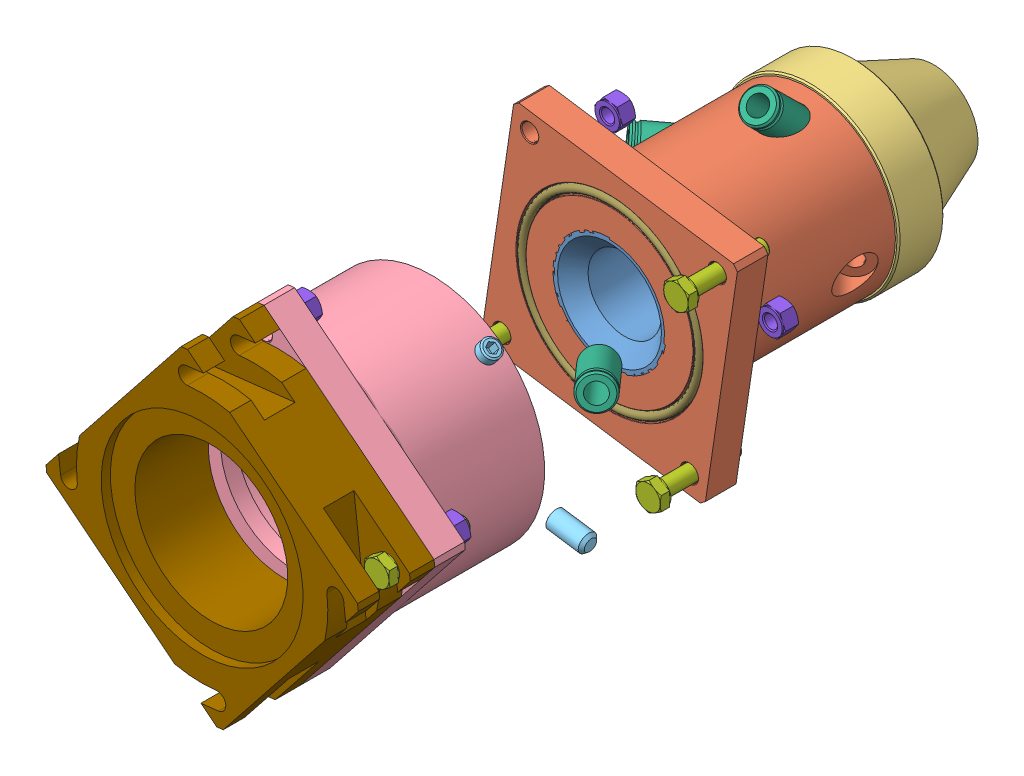
SolidWorks assembly 0Montagem _BOM, configuration Valor predeterminado. Lengths in mm.
Overall size (109.44 103.97 239.19).
36 component instances, 14 part files, 67 mates.
Components (placement in the parent):
- 1Câmara de mistura-1: 1Câmara de mistura [Valor predeterminado] at (-3.7067 1.39 80) size (39.8 39.8 80)
- 2Invólucro-1: 2Invólucro [Valor predeterminado] at (-3.7067 1.39 79.5) x (-0.989121 0.147103 0) z (0 0 1) size (74 74 80)
- 3bocal_interno-1: 3bocal_interno [Valor predeterminado] at (-3.7067 1.39 -19.2681) x (0.242577 -0.970132 0) z (-0.970132 -0.242577 0) size (37.18 39 37.18) (hidden)
- 4bocal_externo-1: 4bocal_externo [Valor predeterminado] at (-3.7067 1.39 -20.5) x (0.998618 -0.052557 0) z (-0.052557 -0.998618 0) size (59 41 59)
- Separador Inferior-1: Separador Inferior [Valor predeterminado] at (-3.7067 1.39 79.5) x (0.147103 0.989121 0) z (0 0 1) size (74 74 91.5) (hidden)
- Separador Superior-1: Separador Superior [Valor predeterminado] at (-3.7067 1.39 177.6934) x (-0.783053 0.621956 0) z (0 0 1) size (74 74 50)
- socket set screw flat point_iso-8: socket set screw flat point_iso [ISO 4026 - M6 x 12-N] at (21.1716 32.7121 142.6934) x (-0.621956 -0.783053 0) z (-0.41719 0.331362 0.846257) size (12 6 6)
- socket set screw flat point_iso-10: socket set screw flat point_iso [ISO 4026 - M6 x 12-N] at (-7.5043 11.0106 142.6934) x (-0.367166 0.930156 0) z (0.914857 0.361127 -0.180621) size (12 6 6) (hidden)
- socket set screw flat point_iso-15: socket set screw flat point_iso [ISO 4026 - M6 x 12-N] at (41.4083 -5.3195 142.6934) x (0.989121 -0.147103 0) z (-0.009687 -0.065137 -0.997829) size (12 6 6)
- conector_reto_aventics_1823373040-1: conector_reto_aventics_1823373040 [Valor predeterminado] at (-7.3078 -22.8243 23.4105) x (0.664276 -0.577991 -0.473986) z (0.104018 0.699414 -0.707107) size (10.5 10.5 22.5) (hidden)
- conector_reto_aventics_1823373040-2: conector_reto_aventics_1823373040 [Valor predeterminado] at (-7.9051 -26.8402 109.3995) x (0.664276 -0.577991 -0.473986) z (0.104018 0.699414 -0.707107) size (10.5 10.5 22.5)
- conector_reto_aventics_1823373040-3: conector_reto_aventics_1823373040 [Valor predeterminado] at (-27.9209 4.9912 23.4105) x (0.588702 -0.477165 0.65249) z (0.699414 -0.104018 -0.707107) size (10.5 10.5 22.5)
- conector_reto_aventics_1823373040-4: conector_reto_aventics_1823373040 [Valor predeterminado] at (-26.0555 19.141 109.3995) x (0.396766 -0.607235 0.688362) z (0.553702 -0.439789 -0.707107) size (10.5 10.5 22.5) (hidden)
- conector_reto_aventics_1823373040-5: conector_reto_aventics_1823373040 [Valor predeterminado] at (22.8406 11.8691 109.3995) x (0.551622 -0.805255 -0.217432) z (-0.657719 -0.259625 -0.707107) size (10.5 10.5 22.5)
- conector_reto_aventics_1823373040-6: conector_reto_aventics_1823373040 [Valor predeterminado] at (-0.1055 25.6043 23.4105) x (0.13653 -0.714274 0.68642) z (-0.104018 -0.699414 -0.707107) size (10.5 10.5 22.5)
- conector_reto_aventics_1823373040-8: conector_reto_aventics_1823373040 [Valor predeterminado] at (20.5076 -2.2112 23.4105) x (0.420411 -0.740215 -0.524725) z (-0.699414 0.104018 -0.707107) size (10.5 10.5 22.5) (hidden)
- hex screw gradeab_iso-1: hex screw gradeab_iso [ISO 4017 - M5 x 25-N] at (-38.9296 -24.7126 93) x (0 0 -1) z (1 0 0) size (28.5 9.24 8)
- hex screw gradeab_iso-3: hex screw gradeab_iso [ISO 4017 - M5 x 25-N] at (-29.8092 36.6129 93) x (0 0 -1) z (1 0 0) size (28.5 9.24 8) (hidden)
- hex screw gradeab_iso-4: hex screw gradeab_iso [ISO 4017 - M5 x 25-N] at (31.5163 27.4926 93) x (0 0 -1) z (1 0 0) size (28.5 9.24 8)
- hex screw gradeab_iso-5: hex screw gradeab_iso [ISO 4017 - M5 x 25-N] at (22.3959 -33.833 93) x (0 0 -1) z (1 0 0) size (28.5 9.24 8)
- hex nut style 2 gradeab_iso-1: hex nut style 2 gradeab_iso [ISO - 4033 - M5 - W - N] at (-14.484 43.8853 64.4) x (0.923728 0.383049 0) z (0 0 -1) size (8 9.24 5.1)
- hex nut style 2 gradeab_iso-2: hex nut style 2 gradeab_iso [ISO - 4033 - M5 - W - N] at (-46.2019 -9.3873 64.4) x (0.923728 0.383049 0) z (0 0 -1) size (8 9.24 5.1)
- hex nut style 2 gradeab_iso-3: hex nut style 2 gradeab_iso [ISO - 4033 - M5 - W - N] at (38.7886 12.1673 64.4) x (0.923728 0.383049 0) z (0 0 -1) size (8 9.24 5.1)
- hex nut style 2 gradeab_iso-4: hex nut style 2 gradeab_iso [ISO - 4033 - M5 - W - N] at (7.0707 -41.1053 63.4) x (0.923728 0.383049 0) z (0 0 -1) size (8 9.24 5.1)
- hex nut style 2 gradeab_iso-5: hex nut style 2 gradeab_iso [ISO - 4033 - M5 - W - N] at (1.2873 -42.1653 172.5934) x (0.877581 0.479428 0) z (0 0 -1) size (8 9.24 5.1) (hidden)
- hex nut style 2 gradeab_iso-6: hex nut style 2 gradeab_iso [ISO - 4033 - M5 - W - N] at (39.8486 6.384 172.5934) x (0.923728 0.383049 0) z (0 0 -1) size (8 9.24 5.1)
- hex nut style 2 gradeab_iso-7: hex nut style 2 gradeab_iso [ISO - 4033 - M5 - W - N] at (-8.7007 44.9452 172.5934) x (0.894482 0.447104 0) z (0 0 -1) size (8 9.24 5.1)
- hex nut style 2 gradeab_iso-8: hex nut style 2 gradeab_iso [ISO - 4033 - M5 - W - N] at (-47.2619 -3.604 172.5934) x (0.923728 0.383049 0) z (0 0 -1) size (8 9.24 5.1)
- acoplamento_espaçador_precitec (1)-3: acoplamento_espaçador_precitec (1) [Valor predeterminado] at (-55.692 -4.5706 187.6934) x (0 0 1) z (-0.783053 0.621956 0) size (27 74 74)
- hex screw gradeab_iso-6: hex screw gradeab_iso [ISO 4017 - M5 x 25-N] at (-8.7007 44.9452 199.1934) x (0 0 -1) z (-0.865163 0.501491 0) size (28.5 9.24 8) (hidden)
- hex screw gradeab_iso-8: hex screw gradeab_iso [ISO 4017 - M5 x 25-N] at (1.2873 -42.1653 199.1934) x (0 0 -1) z (1 0 0) size (28.5 9.24 8) (hidden)
- hex screw gradeab_iso-9: hex screw gradeab_iso [ISO 4017 - M5 x 25-N] at (-47.2619 -3.604 199.1934) x (0 0 -1) z (0.936859 0.349707 0) size (28.5 9.24 8)
- hex screw gradeab_iso-10: hex screw gradeab_iso [ISO 4017 - M5 x 25-N] at (39.8486 6.384 199.1934) x (0 0 -1) z (0.997971 0.063675 0) size (28.5 9.24 8)
- Parker Mod. 2-143 - Material Etileno Propileno(EPDM)-Vedação Estática Cilíndrica-1: Parker Mod. 2-143 - Material Etileno Propileno(EPDM)-Vedação Estática Cilíndrica [Valor predeterminado] at (-3.7067 1.39 165.51) x (0.999508 0.031367 0) z (0 0 1) size (66.84 66.84 2.62)
- Parker Mod. 2-038 - Material Etileno Propileno(EPDM)-Vedação de Face-1: Parker Mod. 2-038 - Material Etileno Propileno(EPDM)-Vedação de Face [Valor predeterminado] at (-3.7067 1.39 188.3034) x (-0.157479 -0.987522 0) z (0 0 1) size (69.96 69.96 1.78)
- Parker Mod. 2-139 - Material Etileno Propileno(EPDM)-Vedação de Face-1: Parker Mod. 2-139 - Material Etileno Propileno(EPDM)-Vedação de Face [Valor predeterminado] at (-3.7067 1.39 78.81) x (0.912781 0.408449 0) z (0 0 1) size (60.49 60.49 2.62)
Mates (geometry in assembly coordinates):
- Concêntrico1: concentric: circle of 1Câmara de mistura-1; circle of 2Invólucro-1
- Coincidente1: coincident: plane of 1Câmara de mistura-1 through (-3.7067 13.39 79.5) normal (0 0 1); plane of 2Invólucro-1 through (-6.6487 -18.3924 79.5) normal (0 0 1)
- Concêntrico2: concentric: circle of 1Câmara de mistura-1; circle of 3bocal_interno-1
- Coincidente2: coincident: plane of 1Câmara de mistura-1 through (-3.7067 12.39 -0.5) normal (0 0 -1); plane of 3bocal_interno-1 through (-3.7067 1.39 -0.5) normal (0 0 1)
- Concêntrico3: concentric: circle of 3bocal_interno-1; circle of 4bocal_externo-1
- Coincidente3: coincident: plane of 2Invólucro-1 through (-6.7958 -19.3815 14.5) normal (0 0 -1); plane of 4bocal_externo-1 through (-2.1562 30.8492 14.5) normal (0 0 1)
- Concêntrico4: concentric: circle of 3bocal_interno-1; circle of Separador Inferior-1
- Coincidente4: coincident: plane of 2Invólucro-1 through (-6.6487 -18.3924 79.5) normal (0 0 1); plane of Separador Inferior-1 through (-3.7067 1.39 79.5) normal (0 0 -1)
- Concêntrico6: concentric: cylinder of 2Invólucro-1 through (-29.8092 36.6129 79.5) axis (0 0 1) radius 2.75; circle of Separador Inferior-1
- Concêntrico121: concentric: cylinder of Separador Superior-1 through (19.3057 30.3629 142.6934) axis (0.621956 0.783053 0) radius 2.5; cylinder of socket set screw flat point_iso-8 through (29.0704 42.6569 142.6934) axis (0.621956 0.783053 0) radius 3
- Concêntrico14: concentric: cylinder of Separador Superior-1 through (9.8785 -33.0258 142.6934) axis (0.367166 -0.930156 0) radius 2.5; cylinder of socket set screw flat point_iso-10 through (-2.8413 -0.8023 142.6934) axis (0.367166 -0.930156 0) radius 3
- Concêntrico16: concentric: cylinder of Separador Superior-1 through (-40.3041 6.8328 142.6934) axis (-0.989121 0.147103 0) radius 2.5; cylinder of socket set screw flat point_iso-15 through (28.8465 -3.4513 142.6934) axis (-0.989121 0.147103 0) radius 3
- Concêntrico17: concentric: circle of 2Invólucro-1; circle of conector_reto_aventics_1823373040-1
- Coincidente12: coincident: plane of 2Invólucro-1 through (-7.0478 -21.0757 25.1782) normal (-0.104018 -0.699414 0.707107); plane of conector_reto_aventics_1823373040-1 through (-6.8932 -17.373 28.8634) normal (0.104018 0.699414 -0.707107)
- Concêntrico18: concentric: circle of Separador Inferior-1; circle of conector_reto_aventics_1823373040-2
- Coincidente13: coincident: plane of Separador Inferior-1 through (-7.645 -25.0916 111.1673) normal (-0.104018 -0.699414 0.707107); plane of conector_reto_aventics_1823373040-2 through (-7.4905 -21.3889 114.8525) normal (0.104018 0.699414 -0.707107)
- Concêntrico19: concentric: circle of 2Invólucro-1; circle of conector_reto_aventics_1823373040-3
- Coincidente14: coincident: plane of 2Invólucro-1 through (-26.1724 4.7311 25.1782) normal (-0.699414 0.104018 0.707107); plane of conector_reto_aventics_1823373040-3 through (-28.9224 12.3611 21.3357) normal (0.699414 -0.104018 -0.707107)
- Concêntrico20: concentric: circle of Separador Inferior-1; circle of conector_reto_aventics_1823373040-4
- Coincidente15: coincident: plane of Separador Inferior-1 through (-24.6712 18.0415 111.1673) normal (-0.553702 0.439789 0.707107); plane of conector_reto_aventics_1823373040-4 through (-24.2245 26.0694 106.5241) normal (0.553702 -0.439789 -0.707107)
- Concêntrico21: concentric: circle of Separador Inferior-1; circle of conector_reto_aventics_1823373040-5
- Coincidente16: coincident: plane of Separador Inferior-1 through (21.1963 11.2201 111.1673) normal (0.657719 0.259625 0.707107); plane of conector_reto_aventics_1823373040-5 through (22.6295 19.1764 106.9129) normal (-0.657719 -0.259625 -0.707107)
- Concêntrico22: concentric: circle of 2Invólucro-1; circle of conector_reto_aventics_1823373040-6
- Coincidente17: coincident: plane of 2Invólucro-1 through (-0.3655 23.8557 25.1782) normal (0.104018 0.699414 0.707107); plane of conector_reto_aventics_1823373040-6 through (4.528 29.6415 18.7356) normal (-0.104018 -0.699414 -0.707107)
- Concêntrico23: concentric: circle of 2Invólucro-1; circle of conector_reto_aventics_1823373040-8
- Coincidente18: coincident: plane of 2Invólucro-1 through (18.7591 -1.9511 25.1782) normal (0.699414 -0.104018 0.707107); plane of conector_reto_aventics_1823373040-8 through (21.368 5.4573 23.6875) normal (-0.699414 0.104018 -0.707107)
- Concêntrico122: concentric: cone of Separador Inferior-1 through (-38.9296 -24.7126 89.25) axis (0 0 -1); cylinder of hex screw gradeab_iso-1 through (-38.9296 -24.7126 93) axis (0 0 1) radius 4
- Coincidente19: coincident: plane of Separador Inferior-1 through (-3.7067 1.39 89.5) normal (0 0 1); plane of hex screw gradeab_iso-1 through (-38.9296 -20.0938 89.5) normal (0 0 -1)
- Concêntrico123: concentric: cone of Separador Inferior-1 through (-29.8092 36.6129 89.25) axis (0 0 -1); cylinder of hex screw gradeab_iso-3 through (-29.8092 36.6129 93) axis (0 0 1) radius 4
- Coincidente20: coincident: plane of Separador Inferior-1 through (-3.7067 1.39 89.5) normal (0 0 1); plane of hex screw gradeab_iso-3 through (-29.8092 41.2317 89.5) normal (0 0 -1)
- Concêntrico124: concentric: cone of Separador Inferior-1 through (31.5163 27.4926 89.25) axis (0 0 -1); cylinder of hex screw gradeab_iso-4 through (31.5163 27.4926 93) axis (0 0 1) radius 4
- Coincidente21: coincident: plane of Separador Inferior-1 through (-3.7067 1.39 89.5) normal (0 0 1); plane of hex screw gradeab_iso-4 through (31.5163 32.1114 89.5) normal (0 0 -1)
- Concêntrico125: concentric: cone of Separador Inferior-1 through (22.3959 -33.833 89.25) axis (0 0 -1); cylinder of hex screw gradeab_iso-5 through (22.3959 -33.833 93) axis (0 0 1) radius 4
- Coincidente22: coincident: plane of Separador Inferior-1 through (-3.7067 1.39 89.5) normal (0 0 1); plane of hex screw gradeab_iso-5 through (22.3959 -29.2142 89.5) normal (0 0 -1)
- Concêntrico151: concentric: circle of Separador Inferior-1; circle of acoplamento_espaçador_precitec (1)-3
- Coincidente50: coincident: plane of Separador Superior-1 through (-3.7067 1.39 187.6934) normal (0 0 1); plane of acoplamento_espaçador_precitec (1)-3 through (-55.692 -4.5706 187.6934) normal (0 0 -1)
- Coincidente51: coincident: plane of Separador Superior-1 through (-55.692 -4.5706 187.6934) normal (-0.783053 0.621956 0); plane of acoplamento_espaçador_precitec (1)-3 through (-55.692 -4.5706 212.6934) normal (-0.783053 0.621956 0)
- Coincidente52: coincident: plane of Separador Superior-1 through (2.2539 -50.5953 187.6934) normal (0.783053 -0.621956 0); plane of acoplamento_espaçador_precitec (1)-3 through (2.2539 -50.5953 212.6934) normal (0.783053 -0.621956 0)
- Concêntrico1541: concentric: cylinder of Separador Superior-1 through (1.2873 -42.1653 187.6934) axis (0 0 1) radius 2.75; cylinder of hex screw gradeab_iso-8 through (1.2873 -42.1653 199.1934) axis (0 0 1) radius 4
- Concêntrico155: concentric: cylinder of Separador Superior-1 through (1.2873 -42.1653 187.6934) axis (0 0 1) radius 2.75; cylinder of hex screw gradeab_iso-8 through (1.2873 -42.1653 199.1934) axis (0 0 1) radius 2.5
- Coincidente54: coincident: plane of acoplamento_espaçador_precitec (1)-3 through (-30.3808 14.5622 195.6934) normal (0 0 1); plane of hex screw gradeab_iso-8 through (1.2873 -37.5465 195.6934) normal (0 0 -1)
- Coincidente55: coincident: plane of acoplamento_espaçador_precitec (1)-3 through (-58.5412 20.2665 195.6934) normal (0 0 1); circle of hex screw gradeab_iso-9
- Concêntrico157: concentric: cylinder of Separador Superior-1 through (-47.2619 -3.604 187.6934) axis (0 0 1) radius 2.75; cylinder of hex screw gradeab_iso-9 through (-47.2619 -3.604 199.1934) axis (0 0 1) radius 2.5
- Concêntrico159: concentric: cylinder of hex nut style 2 gradeab_iso-8 through (-47.2619 -3.604 177.6934) axis (0 0 -1) radius 2.1; cylinder of hex screw gradeab_iso-9 through (-47.2619 -3.604 199.1934) axis (0 0 1) radius 2.5
- Concêntrico160: concentric: cylinder of hex nut style 2 gradeab_iso-5 through (1.2873 -42.1653 177.6934) axis (0 0 -1) radius 2.1; cylinder of hex screw gradeab_iso-8 through (1.2873 -42.1653 199.1934) axis (0 0 1) radius 2.5
- Concêntrico161: concentric: cylinder of Separador Superior-1 through (-8.7007 44.9452 187.6934) axis (0 0 1) radius 2.75; cylinder of hex screw gradeab_iso-6 through (-8.7007 44.9452 199.1934) axis (0 0 1) radius 2.5
- Coincidente60: coincident: plane of acoplamento_espaçador_precitec (1)-3 through (15.1699 56.2245 195.6934) normal (0 0 1); plane of hex screw gradeab_iso-6 through (-11.017 40.9492 195.6934) normal (0 0 -1)
- Concêntrico162: concentric: cylinder of hex nut style 2 gradeab_iso-7 through (-8.7007 44.9452 177.6934) axis (0 0 -1) radius 2.1; cylinder of hex screw gradeab_iso-6 through (-8.7007 44.9452 199.1934) axis (0 0 1) radius 2.5
- Concêntrico163: concentric: cylinder of acoplamento_espaçador_precitec (1)-3 through (39.8486 6.384 195.6934) axis (0 0 -1) radius 2.75; cylinder of hex screw gradeab_iso-10 through (39.8486 6.384 199.1934) axis (0 0 1) radius 4
- Coincidente62: coincident: plane of acoplamento_espaçador_precitec (1)-3 through (45.4322 32.188 195.6934) normal (0 0 1); plane of hex screw gradeab_iso-10 through (39.5545 10.9934 195.6934) normal (0 0 -1)
- Concêntrico164: concentric: cylinder of hex nut style 2 gradeab_iso-6 through (39.8486 6.384 177.6934) axis (0 0 -1) radius 2.1; cylinder of hex screw gradeab_iso-10 through (39.8486 6.384 199.1934) axis (0 0 1) radius 2.5
- Concêntrico1542: concentric: cylinder of Separador Inferior-1 through (-3.7067 1.39 171) axis (0 0 1) radius 30.9; circle of Parker Mod. 2-143 - Material Etileno Propileno(EPDM)-Vedação Estática Cilíndrica-1
- Tangente2: tangent: plane of Separador Inferior-1 through (-36.3477 6.2444 164.2) normal (0 0 1); torus of Parker Mod. 2-143 - Material Etileno Propileno(EPDM)-Vedação Estática Cilíndrica-1
- Concêntrico1543: concentric: cylinder of acoplamento_espaçador_precitec (1)-3 through (-3.7067 1.39 185.6934) axis (0 0 1) radius 33; circle of Parker Mod. 2-038 - Material Etileno Propileno(EPDM)-Vedação de Face-1
- Tangente4: tangent: plane of acoplamento_espaçador_precitec (1)-3 through (-3.7067 1.39 189.1934) normal (0 0 -1); torus of Parker Mod. 2-038 - Material Etileno Propileno(EPDM)-Vedação de Face-1
- Concêntrico1544: concentric: cylinder of 2Invólucro-1 through (-3.7067 1.39 79.5) axis (0 0 1) radius 27.385; circle of Parker Mod. 2-139 - Material Etileno Propileno(EPDM)-Vedação de Face-1
- Tangente6: tangent: plane of 2Invólucro-1 through (-33.86 5.8744 77.5) normal (0 0 1); torus of Parker Mod. 2-139 - Material Etileno Propileno(EPDM)-Vedação de Face-1
- Coincidente63: coincident: plane of Separador Superior-1 through (-3.7067 1.39 177.6934) normal (0 0 -1); plane of hex nut style 2 gradeab_iso-7 through (-6.6356 40.8138 177.6934) normal (0 0 1)
- Coincidente64: coincident: plane of Separador Superior-1 through (-3.7067 1.39 177.6934) normal (0 0 -1); plane of hex nut style 2 gradeab_iso-8 through (-45.4927 -7.8705 177.6934) normal (0 0 1)
- Coincidente65: coincident: plane of Separador Superior-1 through (-3.7067 1.39 177.6934) normal (0 0 -1); plane of hex nut style 2 gradeab_iso-5 through (3.5017 -46.2186 177.6934) normal (0 0 1)
- Coincidente66: coincident: plane of Separador Superior-1 through (-3.7067 1.39 177.6934) normal (0 0 -1); plane of hex nut style 2 gradeab_iso-6 through (41.6178 2.1175 177.6934) normal (0 0 1)
- Coincidente67: coincident: plane of 2Invólucro-1 through (-11.4296 -50.5389 69.5) normal (0 0 -1); plane of hex nut style 2 gradeab_iso-2 through (-44.4327 -13.6538 69.5) normal (0 0 1)
- Coincidente71: coincident: plane of 2Invólucro-1 through (-11.4296 -50.5389 69.5) normal (0 0 -1); plane of hex nut style 2 gradeab_iso-1 through (-12.7148 39.6188 69.5) normal (0 0 1)
- Coincidente72: coincident: plane of 2Invólucro-1 through (-11.4296 -50.5389 69.5) normal (0 0 -1); plane of hex nut style 2 gradeab_iso-3 through (40.5579 7.9008 69.5) normal (0 0 1)
- Concêntrico1545: concentric: circle of Separador Inferior-1; circle of acoplamento_espaçador_precitec (1)-3
- Concêntrico1546: concentric: circle of Separador Superior-1; circle of acoplamento_espaçador_precitec (1)-3
- Coincidente75: coincident: plane of Separador Inferior-1 through (12.1704 24.5368 159.05) normal (0.621956 0.783053 0); plane of socket set screw flat point_iso-8 through (15.0334 22.2628 143.759) normal (-0.621956 -0.783053 0)
